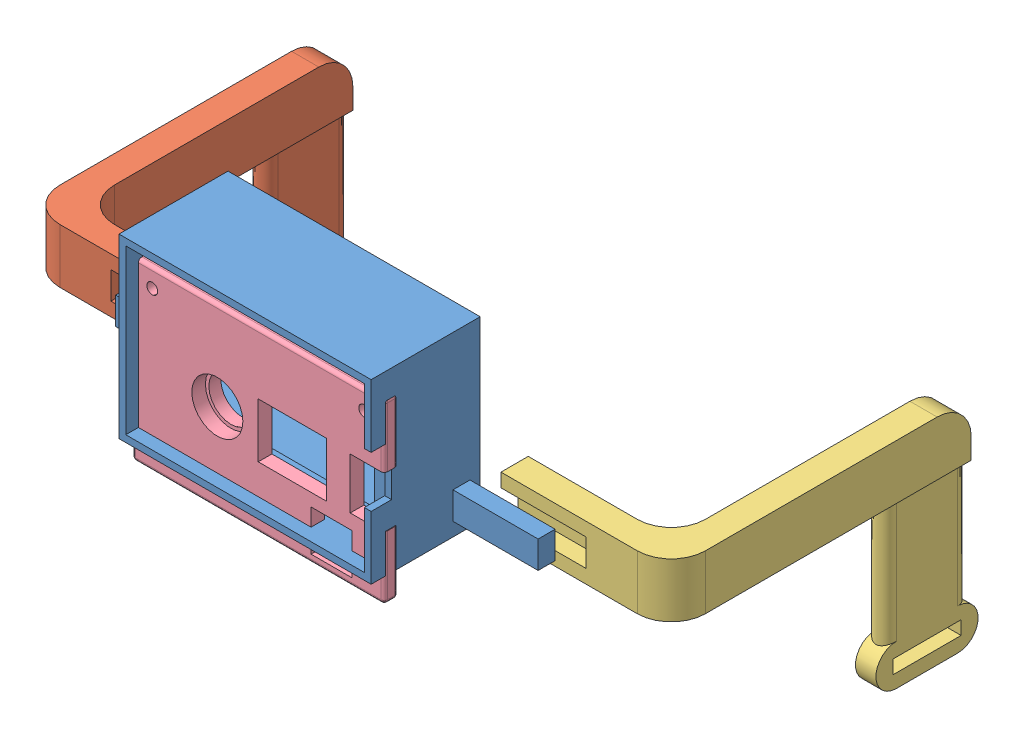
SolidWorks assembly Hololens 1 Assembly, configuration Default. Lengths in mm.
Overall size (187.95 99.9 122.17).
4 component instances, 4 part files, 0 mates.
Components (placement in the parent):
- Hololens 1 Bottom-1: Hololens 1 Bottom [Default] at (45.4519 68.9655 80.7296) x (1 0 0) z (0 -1 0) size (124 32 52)
- Hololens 1 Left Arm-1: Hololens 1 Left Arm [Default] at (1.4211 51.0618 79.0593) x (0 1 0) z (-1 0 0) size (64 91 50)
- Hololens 1 Right Arm-1: Hololens 1 Right Arm [Default] at (89.376 51.3502 77.5613) x (0 -1 0) z (1 0 0) size (64 91 50)
- Oculus Quest 2 Top-1: Oculus Quest 2 Top [Default] at (45.6244 61.8226 109.0391) x (1 0 0) z (0 0 -1) size (74 52 7.5)
